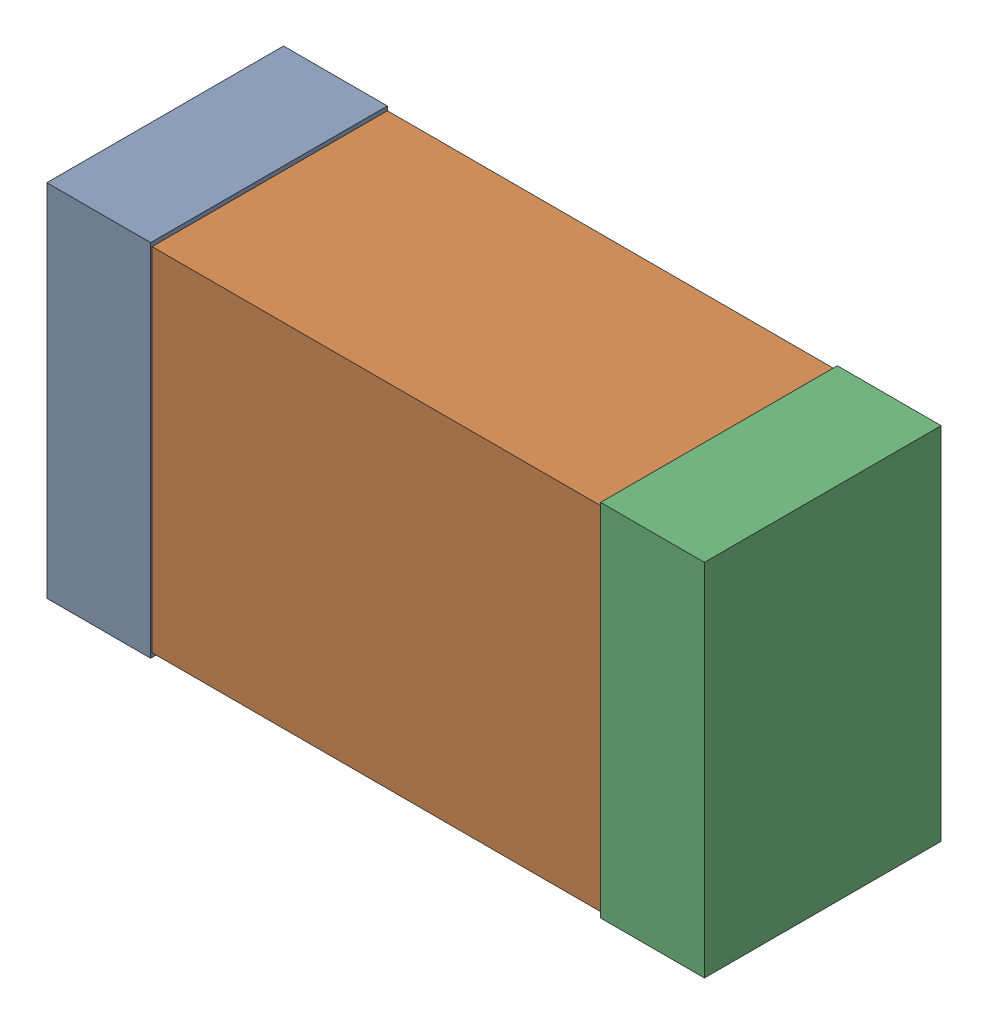
SolidWorks assembly C14_Motor_1Kanaloa_v2.0.0_Motor, configuration Default. Lengths in mm.
Overall size (2.38 1.3 0.85).
6 component instances, 2 part files, 0 mates.
Components (placement in the parent):
- 352877648-1: 352877648 [Default] at (76.74 55.88 0) size (0.38 1.3 0.85)
  - Extruded_14-1: Extruded_14 [Default] at origin size (0.38 1.3 0.85)
- 352877392-1: 352877392 [Default] at (77.74 55.88 0) size (2.2 1.27 0.85)
  - Extruded_15-1: Extruded_15 [Default] at origin size (2.2 1.27 0.85)
- 352877648-2: 352877648 [Default] at (78.74 55.88 0) size (0.38 1.3 0.85)
  - Extruded_14-1: Extruded_14 [Default] at origin size (0.38 1.3 0.85)
